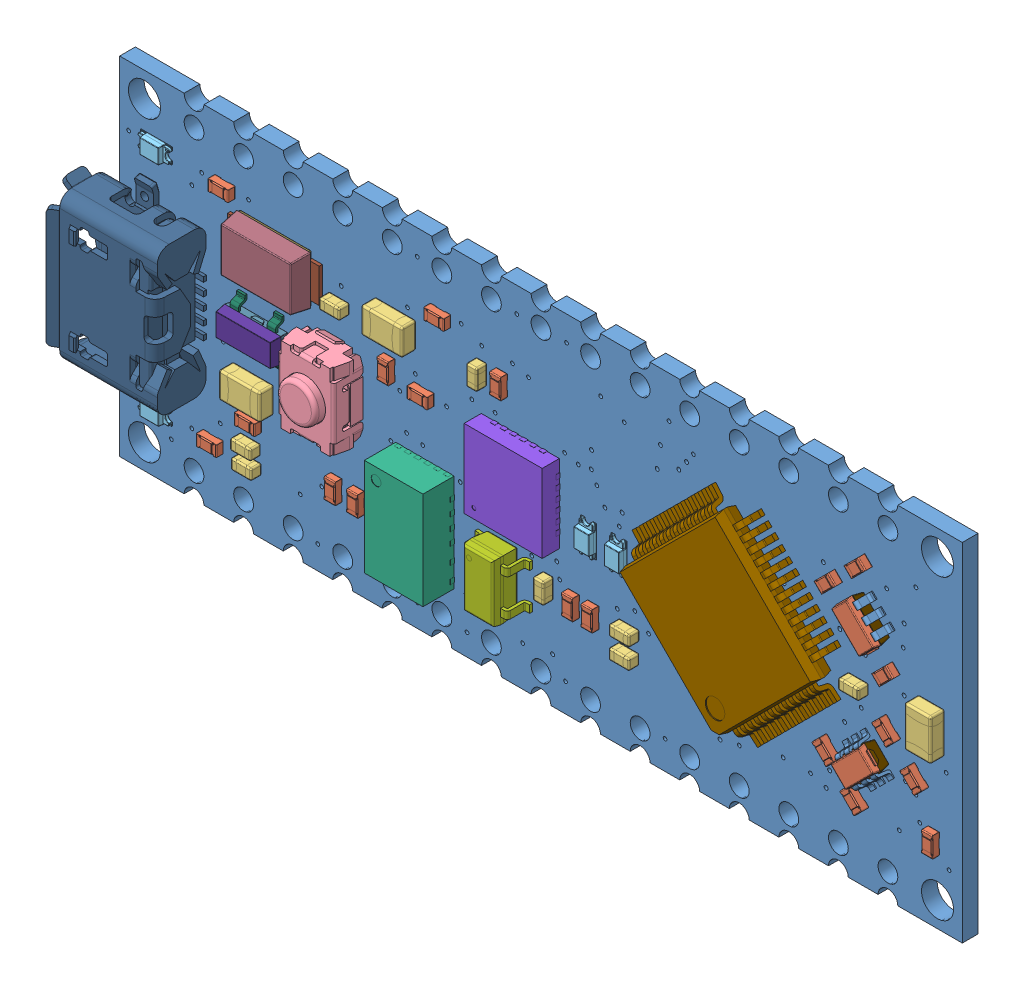
SolidWorks assembly NANOEveryV3.0, configuration Default. Lengths in mm.
Overall size (44.29 17.78 3.62).
78 component instances, 21 part files, 0 mates.
Components (placement in the parent):
- NANOEveryV3.0.step-1: NANOEveryV3.0.step [Default] at origin size (44.29 17.78 3.62)
  - PCB Component.step-1: PCB Component.step [Default] at origin size (43.18 17.78 2.82)
    - Board.step-1: Board.step [Default] at origin size (43.18 17.78 0.81)
    - DNP.step-1: DNP.step [Default] at (6.768 4.975 0.805) x (-1 0 0) z (0 0 1) size (1.05 0.55 0.4)
    - DNP.step-2: DNP.step [Default] at (5.4 14.7 0.805) size (1.05 0.55 0.4)
    - DNP.step-3: DNP.step [Default] at (4.8 3.088 0.805) size (1.05 0.55 0.4)
    - DNP.step-4: DNP.step [Default] at (11.138 4.225 0.805) x (0 -1 0) z (0 0 1) size (1.05 0.55 0.4)
    - DNP.step-5: DNP.step [Default] at (12.275 4.225 0.805) x (0 1 0) z (0 0 1) size (1.05 0.55 0.4)
    - DNP.step-6: DNP.step [Default] at (13.85 10.9 0.805) x (0 -1 0) z (0 0 1) size (1.05 0.55 0.4)
    - DNP.step-7: DNP.step [Default] at (15.6 10.6 0.805) size (1.05 0.55 0.4)
    - DNP.step-8: DNP.step [Default] at (16.45 14.512 0.805) size (1.05 0.55 0.4)
    - DNP.step-9: DNP.step [Default] at (19.6 13.1 0.805) x (0 1 0) z (0 0 1) size (1.05 0.55 0.4)
    - DNP.step-10: DNP.step [Default] at (36.515 12.794 0.805) x (-0.707107 -0.707107 0) z (0 0 1) size (1.05 0.55 0.4)
    - DNP.step-11: DNP.step [Default] at (41.75 3.85 0.805) x (0 -1 0) z (0 0 1) size (1.05 0.55 0.4)
    - DNP.step-12: DNP.step [Default] at (24.3 5.15 0.805) x (0 -1 0) z (0 0 1) size (1.05 0.55 0.4)
    - DNP.step-13: DNP.step [Default] at (23.3 5.15 0.805) x (0 -1 0) z (0 0 1) size (1.05 0.55 0.4)
    - DNP.step-14: DNP.step [Default] at (39.465 7.644 0.805) x (-0.707107 0.707107 0) z (0 0 1) size (1.05 0.55 0.4)
    - DNP.step-15: DNP.step [Default] at (40.909 6.25 0.805) x (0.707107 -0.707107 0) z (0 0 1) size (1.05 0.55 0.4)
    - DNP.step-16: DNP.step [Default] at (37.835 3.815 0.805) x (0.707107 -0.707107 0) z (0 0 1) size (1.05 0.55 0.4)
    - DNP.step-17: DNP.step [Default] at (36.404 5.254 0.805) x (-0.707107 0.707107 0) z (0 0 1) size (1.05 0.55 0.4)
    - DNP.step-18: DNP.step [Default] at (38.023 14.247 0.805) x (0.707107 0.707107 0) z (0 0 1) size (1.05 0.55 0.4)
    - DNP.step-19: DNP.step [Default] at (39.465 10.165 0.805) x (-0.707107 -0.707107 0) z (0 0 1) size (1.05 0.55 0.4)
    - 22u.step-1: 22u.step [Default] at (6.868 6.475 0.805) size (2.1 1.35 0.75)
    - 22u.step-2: 22u.step [Default] at (14.162 13 0.805) x (-1 0 0) z (0 0 1) size (2.1 1.35 0.75)
    - 22u.step-3: 22u.step [Default] at (41.625 8.89 0.805) x (0 1 0) z (0 0 1) size (2.1 1.35 0.75)
    - PTS820.step-1: PTS820.step [Default] at (11.09 8.89 0.805) x (0 1 0) z (0 0 1) size (4.51 2.91 2.02)
    - YELLOW.step-1: YELLOW.step [Default] at (1.9 3.1 0.805) x (-1 0 0) z (0 0 1) size (1.6 0.8 0.4)
    - YELLOW.step-2: YELLOW.step [Default] at (1.9 14.7 0.805) x (-1 0 0) z (0 0 1) size (1.6 0.8 0.4)
    - YELLOW.step-3: YELLOW.step [Default] at (25.6 8.45 0.805) x (0 -1 0) z (0 0 1) size (1.6 0.8 0.4)
    - YELLOW.step-4: YELLOW.step [Default] at (24.05 8.45 0.805) x (0 -1 0) z (0 0 1) size (1.6 0.8 0.4)
    - MPM3610.step-1: MPM3610.step [Default] at (15.65 5.2 0.805) size (3 5 1.61)
    - AP2112K-3.3.step-1: AP2112K-3.3.step [Default] at (19.762 4.85 0.805) x (0 1 0) z (0 0 1) size (3 2.8 1.4)
    - ATSAMD11D14A.step-1: ATSAMD11D14A.step [Default] at (20.55 9.2 0.805) size (4.02 4.02 0.9)
    - ATMEGA4809.step-1: ATMEGA4809.step [Default] at (31.713 8.887 0.805) x (-0.707107 -0.707107 0) z (0 0 1) size (9.1 9.1 1.2)
  - ZX62-AB-5PA v1.step-1: ZX62-AB-5PA v1.step [Default] at (4.5701 5.4734 1.1691) x (-1 0 0) z (0 1 0) size (5.6 2.95 8.8)
    - Assembly-1.step-1: Assembly-1.step [Default] at origin size (5.6 2.95 8.8)
      - ZX62-AB-5PA (1).step-1: ZX62-AB-5PA (1).step [Default] at (0.08 0 0) size (5.6 2.95 8.8)
  - SOD128 v1.step-1: SOD128 v1.step [Default] at (6.3517 19.8129 -3.8672) x (1 0 0) z (0 -1 0) size (4.7 1.07 2.6)
    - SOD128 Lead.step-1: SOD128 Lead.step [Default] at (-0.626 4.7144 6.0495) size (4.7 0.36 1.75)
    - SOD128 Lower body.step-1: SOD128 Lower body.step [Default] at (-0.126 4.8744 5.6745) x (1 0 0) z (0 0 -1) size (3.7 0.15 2.5)
    - SOD128 Upper body.step-1: SOD128 Upper body.step [Default] at (-0.176 4.8744 8.1745) size (3.8 0.91 2.6)
  - SOT143B v1.step-1: SOT143B v1.step [Default] at (5.9151 11.4516 -0.3943) x (1 0 0) z (0 -1 0) size (2.9 0.95 2.4)
    - SOT143B lower body.step-1: SOT143B lower body.step [Default] at (-0.0896 1.6579 1.5321) x (1 0 0) z (0 0 -1) size (2.9 0.4 1.37)
    - SOT143B small Lead.step-1: SOT143B small Lead.step [Default] at (0.6254 1.5379 1.5468) x (0 0 1) z (-1 0 0) size (0.58 0.45 0.43)
    - SOT143B Large lead.step-1: SOT143B Large lead.step [Default] at (0.1954 1.5379 2.7873) x (0 0 -1) z (1 0 0) size (0.58 0.45 0.83)
    - SOT143B Upper body.step-1: SOT143B Upper body.step [Default] at (-0.0896 1.6579 2.8021) size (2.9 0.5 1.27)
    - SOT143B small Lead.step-2: SOT143B small Lead.step [Default] at (2.5254 1.5379 1.5468) x (0 0 1) z (-1 0 0) size (0.58 0.45 0.43)
    - SOT143B small Lead.step-3: SOT143B small Lead.step [Default] at (2.0954 1.5379 2.7873) x (0 0 -1) z (1 0 0) size (0.58 0.45 0.43)
  - SOT363 v1.step-1: SOT363 v1.step [Default] at (40.2018 5.267 0) x (-0.707107 -0.707107 0) z (-0.707107 0.707107 0) size (2.15 0.95 2.1)
    - SOT353 Lower body.step-1: SOT353 Lower body.step [Default] at (-0.1109 1.3587 1.0026) x (1 0 0) z (0 0 -1) size (2.15 0.58 1.25)
    - SOT353 Lead.step-1: SOT353 Lead.step [Default] at (1.4141 1.3587 2.2526) x (0 0 -1) z (1 0 0) size (0.52 0.76 0.35)
    - SOT353 Upper body.step-1: SOT353 Upper body.step [Default] at (-0.1109 1.3587 2.2126) size (2.15 0.32 1.17)
    - SOT353 Lead.step-2: SOT353 Lead.step [Default] at (0.1141 1.3587 2.2526) x (0 0 -1) z (1 0 0) size (0.52 0.76 0.35)
    - SOT353 Lead.step-3: SOT353 Lead.step [Default] at (0.7641 1.3587 2.2526) x (0 0 -1) z (1 0 0) size (0.52 0.76 0.35)
    - SOT353 Lead.step-4: SOT353 Lead.step [Default] at (0.4641 1.3587 1.0026) x (0 0 1) z (-1 0 0) size (0.52 0.76 0.35)
    - SOT353 Lead.step-5: SOT353 Lead.step [Default] at (1.7641 1.3587 1.0026) x (0 0 1) z (-1 0 0) size (0.52 0.76 0.35)
    - SOT353 Lead.step-6: SOT353 Lead.step [Default] at (1.1141 1.3587 1.0026) x (0 0 1) z (-1 0 0) size (0.52 0.76 0.35)
  - SOD128 v1.step-2: SOD128 v1.step [Default] at (6.3517 19.8129 -3.8672) x (1 0 0) z (0 -1 0) size (4.7 1.07 2.6)
    - SOD128 Lead.step-1: SOD128 Lead.step [Default] at (-0.626 4.7144 6.0495) size (4.7 0.36 1.75)
    - SOD128 Lower body.step-1: SOD128 Lower body.step [Default] at (-0.126 4.8744 5.6745) x (1 0 0) z (0 0 -1) size (3.7 0.15 2.5)
    - SOD128 Upper body.step-1: SOD128 Upper body.step [Default] at (-0.176 4.8744 8.1745) size (3.8 0.91 2.6)
  - SOT363 v1_1.step-1: SOT363 v1_1.step [Default] at (37.9266 10.1897 0) x (-0.707107 0.707107 0) z (0.707107 0.707107 0) size (2.15 0.95 2.1)
    - SOT353 Lower body.step-1: SOT353 Lower body.step [Default] at (-0.1109 1.3587 1.0026) x (1 0 0) z (0 0 -1) size (2.15 0.58 1.25)
    - SOT353 Lead.step-1: SOT353 Lead.step [Default] at (1.4141 1.3587 2.2526) x (0 0 -1) z (1 0 0) size (0.52 0.76 0.35)
    - SOT353 Upper body.step-1: SOT353 Upper body.step [Default] at (-0.1109 1.3587 2.2126) size (2.15 0.32 1.17)
    - SOT353 Lead.step-2: SOT353 Lead.step [Default] at (0.1141 1.3587 2.2526) x (0 0 -1) z (1 0 0) size (0.52 0.76 0.35)
    - SOT353 Lead.step-3: SOT353 Lead.step [Default] at (0.7641 1.3587 2.2526) x (0 0 -1) z (1 0 0) size (0.52 0.76 0.35)
    - SOT353 Lead.step-4: SOT353 Lead.step [Default] at (0.4641 1.3587 1.0026) x (0 0 1) z (-1 0 0) size (0.52 0.76 0.35)
    - SOT353 Lead.step-5: SOT353 Lead.step [Default] at (1.7641 1.3587 1.0026) x (0 0 1) z (-1 0 0) size (0.52 0.76 0.35)
    - SOT353 Lead.step-6: SOT353 Lead.step [Default] at (1.1141 1.3587 1.0026) x (0 0 1) z (-1 0 0) size (0.52 0.76 0.35)
  - CAPC-0402-T0.55-BN v1.step-1: CAPC-0402-T0.55-BN v1.step [Default] at (6.7584 3.0757 0.8042) size (1.05 0.55 0.55)
  - CAPC-0402-T0.55-BN v1.step-2: CAPC-0402-T0.55-BN v1.step [Default] at (6.7495 3.9561 0.8363) size (1.05 0.55 0.55)
  - CAPC-0402-T0.55-BN v1.step-3: CAPC-0402-T0.55-BN v1.step [Default] at (11.3023 12.4773 0.8363) size (1.05 0.55 0.55)
  - CAPC-0402-T0.55-BN v1.step-4: CAPC-0402-T0.55-BN v1.step [Default] at (18.596 13.0887 0.8363) x (0 -1 0) z (0 0 1) size (1.05 0.55 0.55)
  - CAPC-0402-T0.55-BN v1.step-5: CAPC-0402-T0.55-BN v1.step [Default] at (22.0131 5.3081 0.8363) x (0 -1 0) z (0 0 1) size (1.05 0.55 0.55)
  - CAPC-0402-T0.55-BN v1.step-6: CAPC-0402-T0.55-BN v1.step [Default] at (26.1568 5.4049 0.8363) size (1.05 0.55 0.55)
  - CAPC-0402-T0.55-BN v1.step-7: CAPC-0402-T0.55-BN v1.step [Default] at (26.1493 4.3541 0.8363) size (1.05 0.55 0.55)
  - CAPC-0402-T0.55-BN v1.step-8: CAPC-0402-T0.55-BN v1.step [Default] at (37.9079 8.8995 0.8363) size (1.05 0.55 0.55)
